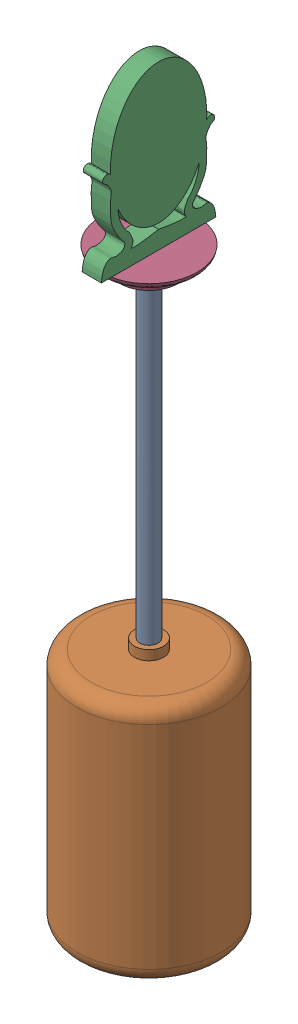
SolidWorks assembly float_assem_mirror, configuration Default. Lengths in mm.
Overall size (42.83 198.86 42.83).
4 component instances, 4 part files, 7 mates.
Components (placement in the parent):
- rod-1: rod [Default] at (9.0948 -80.3774 21.5862) x (0.517339 0 0.85578) z (-0.85578 0 0.517339) size (4.76 100.59 4.76)
- float-1: float [Default] at (9.0948 -133.7174 21.5862) x (0.991129 0 0.132904) z (-0.132904 0 0.991129) size (38.1 66.04 38.1)
- mirror-1: mirror [Default] at (11.6348 46.7378 21.5862) x (0 0 1) z (-1 0 0) size (30.15 42.98 5.08)
- platform-1: platform [Default] at (9.0948 17.0826 21.5862) size (25.4 5.08 25.4)
Mates (geometry in assembly coordinates):
- Concentric2: concentric anti-aligned: circle of rod-1; circle of float-1
- Coincident1: coincident anti-aligned: plane of rod-1 through (9.0948 17.0826 21.5862) normal (0 1 0); plane of platform-1 through (9.0948 17.0826 21.5862) normal (0 -1 0)
- Concentric3: concentric aligned: cylinder of rod-1 through (9.0948 19.6226 21.5862) axis (0 -1 0) radius 2.3813; cylinder of platform-1 through (9.0948 17.0826 21.5862) axis (0 -1 0) radius 1.7272
- Coincident2: coincident anti-aligned: circle of rod-1; plane of float-1 through (9.0948 -67.6774 21.5862) normal (0 1 0)
- Concentric4: concentric aligned: cylinder of mirror-1 through (9.0948 22.1626 21.5862) axis (0 -1 0) radius 1.7272; cylinder of platform-1 through (9.0948 17.0826 21.5862) axis (0 -1 0) radius 1.7272
- Coincident3: coincident aligned: line of mirror-1 through (6.5548 22.1626 6.5125) axis (0 0 1); line of platform-1 through (6.5548 22.1626 14.8425) axis (0 0 1)
- Coincident4: coincident anti-aligned: plane of mirror-1 through (6.5548 22.1626 21.5862) normal (0 -1 0); plane of platform-1 through (9.0948 22.1626 21.5862) normal (0 1 0)
